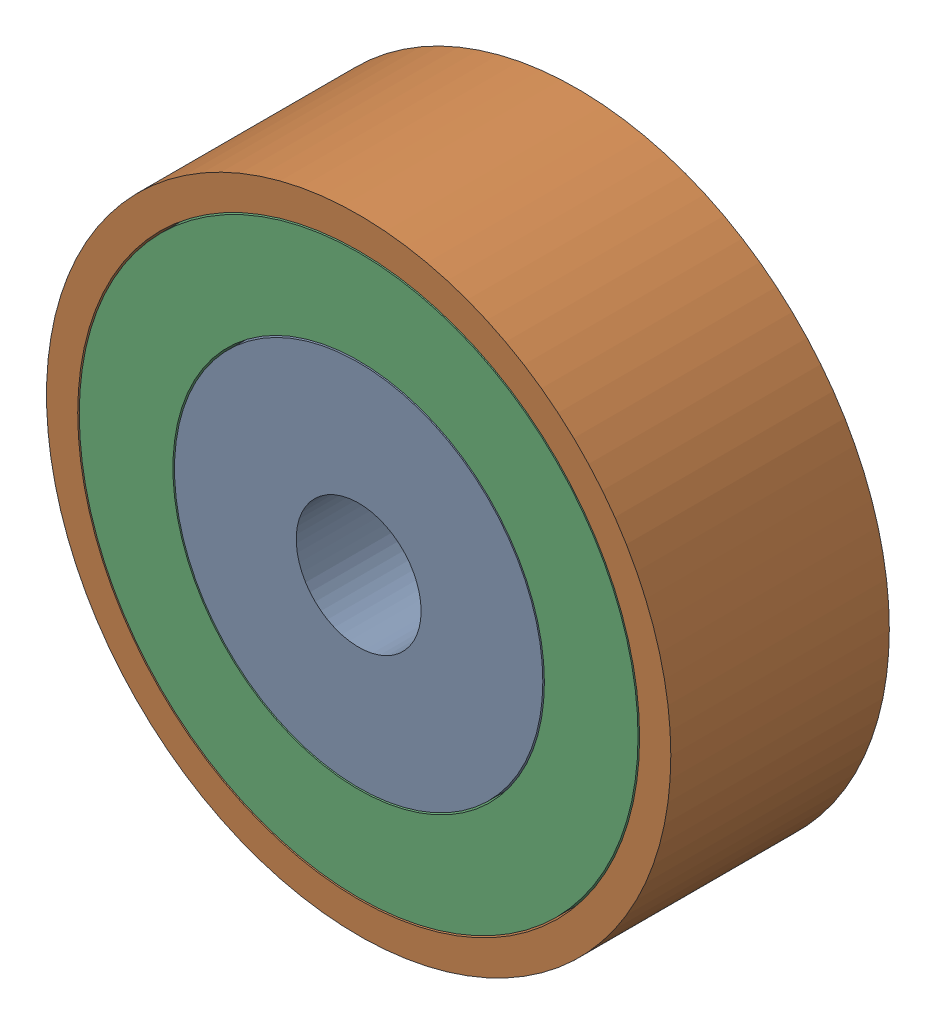
SolidWorks assembly 镜向轴承3, configuration 默认. Lengths in mm.
Overall size (20 20 7).
3 component instances, 3 part files, 4 mates.
Components (placement in the parent):
- 镜向轴承内圈-1: 镜向轴承内圈 [默认] at (-5.0655 0.8032 -6.5) size (11.8 11.8 7)
- 镜向轴承外圈-1: 镜向轴承外圈 [默认] at (-5.0655 0.8032 -6.5) size (20 20 7)
- 镜向轴承中圈-1: 镜向轴承中圈 [默认] at (-5.0655 0.8032 -6.5) size (17.9 17.9 7)
Mates (geometry in assembly coordinates):
- 重合1: coincident: plane of ? through (-5.0655 0.8032 -13.5) normal (0 0 -1); plane of ? through (-5.0655 0.8032 -13.5) normal (0 0 -1)
- 重合2: coincident: plane of ? through (-5.0655 0.8032 -13.5) normal (0 0 -1); plane of ? through (-5.0655 0.8032 -13.5) normal (0 0 -1)
- 同心1: concentric: cylinder of ? through (-5.0655 0.8032 -13.5) axis (0 0 1) radius 9; cylinder of ? through (-5.0655 0.8032 -13.5) axis (0 0 1) radius 8.95
- 同心2: concentric: cylinder of ? through (-5.0655 0.8032 -13.5) axis (0 0 1) radius 5.9; cylinder of ? through (-5.0655 0.8032 -13.5) axis (0 0 1) radius 5.95
